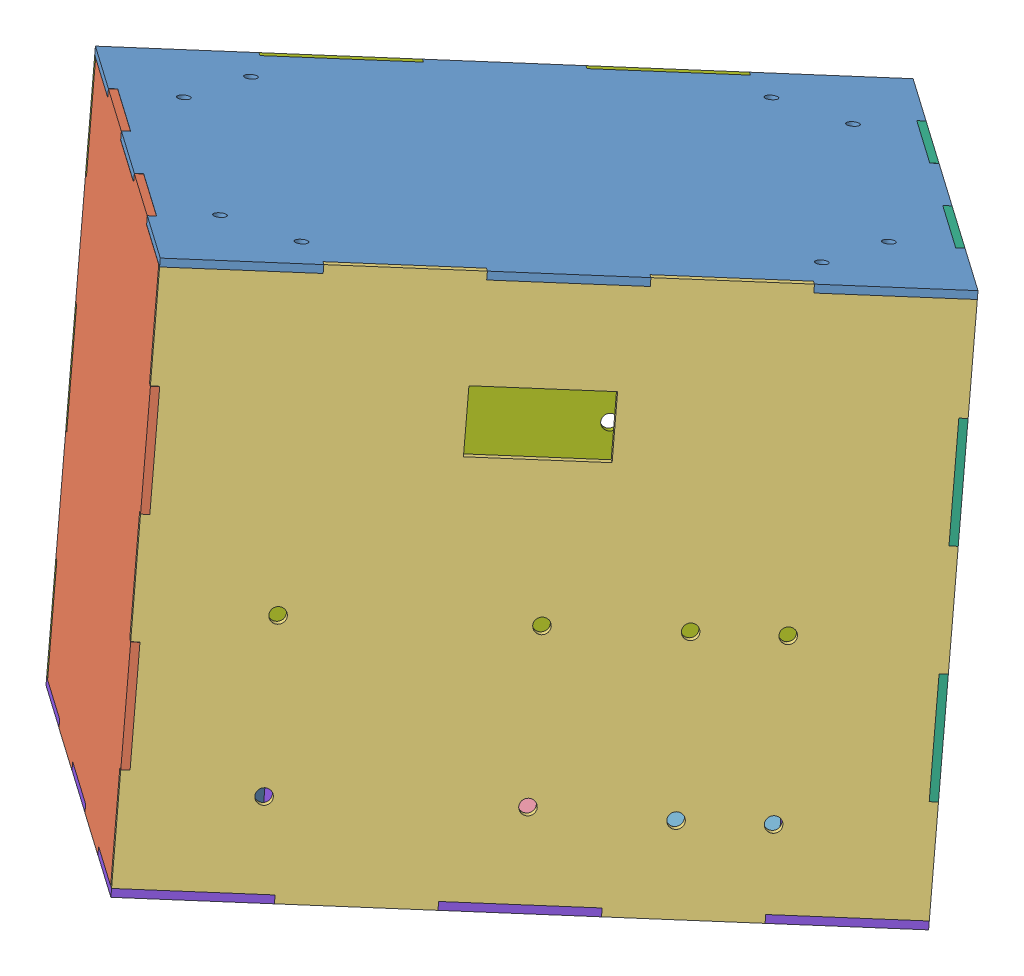
SolidWorks assembly Insideboxassembly, configuration Default. Lengths in mm.
Overall size (387.69 311.14 408.23).
12 component instances, 11 part files, 24 mates.
Components (placement in the parent):
- inside box top-1: inside box top [Default] at (-509.6896 150.6083 -203.9396) x (0.652028 -0.098315 -0.751794) z (0.741694 0.28845 0.605547) size (279.4 3.17 228.6)
- InnerBoxFront-2: InnerBoxFront [Default] at (-581.1313 58.122 -72.2069) x (0.741694 0.28845 0.605547) z (0.157321 -0.952434 0.260997) size (228.6 3.17 228.6) (hidden)
- inside box side2-2: inside box side2 [Default] at (-409.7866 76.8231 -107.645) x (0.652028 -0.098315 -0.751794) z (0.157321 -0.952434 0.260997) size (279.4 3.17 228.6)
- E128solderboard-3: E128solderboard [Default] at (-395.3637 -30.7401 -131.7484) x (0.741694 0.28845 0.605547) z (0.157321 -0.952434 0.260997) size (146.05 82.55 3.81)
- BatteryHolder9V2-1: BatteryHolder9V2 [Default] at (-448.6593 -83.2 -230.2362) x (-0.652028 0.098315 0.751794) z (0.157321 -0.952434 0.260997) size (44.45 6.35 44.45)
- BatteryHolder9V2-3: BatteryHolder9V2 [Default] at (-389.7873 -60.3043 -182.171) x (-0.652028 0.098315 0.751794) z (0.157321 -0.952434 0.260997) size (44.45 6.35 44.45)
- InnerBoxBack-2: InnerBoxBack [Default] at (-403.1893 31.3466 -277.575) x (0.157321 -0.952434 0.260997) z (0.741694 0.28845 0.605547) size (228.6 3.17 228.6) (hidden)
- inside box side1-1: inside box side1 [Default] at (-576.983 11.7993 -244.1503) x (0.652028 -0.098315 -0.751794) z (0.157321 -0.952434 0.260997) size (279.4 3.17 228.6)
- inside box BOTTOM-1: inside box BOTTOM [Default] at (-474.7251 -61.0701 -145.933) x (-0.652028 0.098315 0.751794) z (0.741694 0.28845 0.605547) size (279.4 3.17 228.6)
- ServoHolderHoles-1: ServoHolderHoles [Default] at (-535.694 -31.3874 -73.8537) x (0.741694 0.28845 0.605547) z (0.157321 -0.952434 0.260997) size (76.2 3.17 41.28)
- ServoHolderNoHoles-1: ServoHolderNoHoles [Default] at (-525.343 -32.9481 -85.7884) x (0.741694 0.28845 0.605547) z (0.157321 -0.952434 0.260997) size (76.2 3.17 41.28)
- arrow-1: arrow [Default] at (-684.8622 -261.4435 -156.2484) x (0.157321 -0.952434 0.260997) z (0.741694 0.28845 0.605547) size (101.6 3.17 39.37)
Mates (geometry in assembly coordinates):
- Coincident39: coincident anti-aligned: line of inside box top-1 through (-370.261 175.3374 -197.741) axis (-0.157321 0.952434 -0.260997); line of inside box side2-2 through (-370.7605 178.3614 -198.5697) axis (0.157321 -0.952434 0.260997)
- Coincident40: coincident aligned: line of inside box top-1 through (-370.261 175.3374 -197.741) axis (0.652028 -0.098315 -0.751794); line of inside box side2-2 through (-370.261 175.3374 -197.741) axis (0.652028 -0.098315 -0.751794)
- Coincident41: coincident anti-aligned: line of inside box side1-1 through (-540.3117 112.4217 -336.9976) axis (0.157321 -0.952434 0.260997); line of inside box top-1 through (-539.8123 109.3977 -336.169) axis (-0.157321 0.952434 -0.260997)
- Coincident44: coincident anti-aligned: line of inside box top-1 through (-574.3922 118.8314 -293.0648) axis (0.652028 -0.098315 -0.751794); line of inside box side1-1 through (-537.9569 113.3375 -335.075) axis (-0.652028 0.098315 0.751794)
- Coincident47: coincident anti-aligned: line of InnerBoxFront-2 through (-676.5054 91.7676 -155.1013) axis (-0.157321 0.952434 -0.260997); line of inside box side1-1 through (-683.1986 132.2889 -166.2054) axis (0.157321 -0.952434 0.260997)
- Coincident48: coincident aligned: line of inside box top-1 through (-685.5535 131.3731 -168.128) axis (0.741694 0.28845 0.605547); line of InnerBoxFront-2 through (-683.1986 132.2889 -166.2054) axis (0.741694 0.28845 0.605547)
- Coincident51: coincident anti-aligned: line of InnerBoxBack-2 through (-491.5777 20.2492 -352.7827) axis (-0.157321 0.952434 -0.260997); line of inside box side1-1 through (-498.7539 63.6947 -364.6881) axis (0.157321 -0.952434 0.260997)
- Coincident52: coincident aligned: line of inside box top-1 through (-404.2159 146.8038 -293.5642) axis (0.741694 0.28845 0.605547); line of InnerBoxBack-2 through (-404.2935 146.7736 -293.6276) axis (0.741694 0.28845 0.605547)
- Coincident55: coincident aligned: line of InnerBoxBack-2 through (-402.1626 -84.1106 -261.5858) axis (-0.741694 -0.28845 -0.605547); line of inside box BOTTOM-1 through (-402.1626 -84.1106 -261.5858) axis (-0.741694 -0.28845 -0.605547)
- Coincident56: coincident aligned: line of inside box side2-2 through (-337.1519 -40.2809 -140.8283) axis (0.741694 0.28845 0.605547); line of inside box BOTTOM-1 through (-337.1519 -40.2809 -140.8283) axis (0.741694 0.28845 0.605547)
- Coincident57: coincident aligned: line of inside box side2-2 through (-298.8612 -41.8349 -181.7446) axis (-0.652028 0.098315 0.751794); line of inside box BOTTOM-1 through (-298.8612 -41.8349 -181.7446) axis (-0.652028 0.098315 0.751794)
- Distance1: distance = 12.7 mm aligned: plane of E128solderboard-3 through (-395.3637 -30.7401 -131.7484) normal (-0.157321 0.952434 -0.260997); plane of inside box BOTTOM-1 through (-474.7251 -61.0701 -145.933) normal (-0.157321 0.952434 -0.260997)
- Concentric1: concentric aligned: circle of E128solderboard-3; circle of inside box BOTTOM-1
- Concentric2: concentric aligned: circle of E128solderboard-3; circle of inside box BOTTOM-1
- Coincident58: coincident aligned: line of BatteryHolder9V2-1 through (-448.6593 -83.2 -230.2362) axis (-0.652028 0.098315 0.751794); line of inside box BOTTOM-1 through (-448.6593 -83.2 -230.2362) axis (-0.652028 0.098315 0.751794)
- Coincident59: coincident anti-aligned: line of BatteryHolder9V2-1 through (-461.0804 -81.3271 -215.9146) axis (-0.157321 0.952434 -0.260997); line of inside box BOTTOM-1 through (-461.5799 -78.3031 -216.7432) axis (0.157321 -0.952434 0.260997)
- Coincident60: coincident aligned: line of BatteryHolder9V2-3 through (-389.7873 -60.3043 -182.171) axis (-0.652028 0.098315 0.751794); line of inside box BOTTOM-1 through (-389.7873 -60.3043 -182.171) axis (-0.652028 0.098315 0.751794)
- Coincident61: coincident anti-aligned: line of BatteryHolder9V2-3 through (-402.2084 -58.4314 -167.8493) axis (-0.157321 0.952434 -0.260997); line of inside box BOTTOM-1 through (-402.7079 -55.4074 -168.678) axis (0.157321 -0.952434 0.260997)
- Coincident62: coincident aligned: line of inside box BOTTOM-1 through (-553.6062 -56.5457 -81.8756) axis (0.157321 -0.952434 0.260997); line of ServoHolderHoles-1 through (-553.6062 -56.5457 -81.8756) axis (0.157321 -0.952434 0.260997)
- Coincident63: coincident anti-aligned: line of inside box BOTTOM-1 through (-544.1867 -52.8824 -74.1852) axis (-0.741694 -0.28845 -0.605547); line of ServoHolderHoles-1 through (-544.1482 -52.8674 -74.1537) axis (0.741694 0.28845 0.605547)
- Coincident64: coincident anti-aligned: line of inside box BOTTOM-1 through (-533.3363 -57.4672 -85.2912) axis (-0.741694 -0.28845 -0.605547); line of ServoHolderNoHoles-1 through (-542.7558 -61.1305 -92.9817) axis (0.741694 0.28845 0.605547)
- Coincident65: coincident aligned: line of inside box BOTTOM-1 through (-543.2553 -58.1065 -93.8103) axis (0.157321 -0.952434 0.260997); line of ServoHolderNoHoles-1 through (-543.2553 -58.1065 -93.8103) axis (0.157321 -0.952434 0.260997)
- Distance3: distance = 6.35 mm anti-aligned: plane of arrow-1 through (-542.6388 -36.0448 -66.5981) normal (0.652028 -0.098315 -0.751794); plane of ServoHolderHoles-1 through (-537.7641 -31.0752 -71.4667) normal (-0.652028 0.098315 0.751794)
- Parallel2: parallel aligned: plane of inside box side1-1 through (-576.983 11.7993 -244.1503) normal (-0.741694 -0.28845 -0.605547); plane of arrow-1 through (-555.8261 -41.1734 -77.3647) normal (-0.741694 -0.28845 -0.605547)
